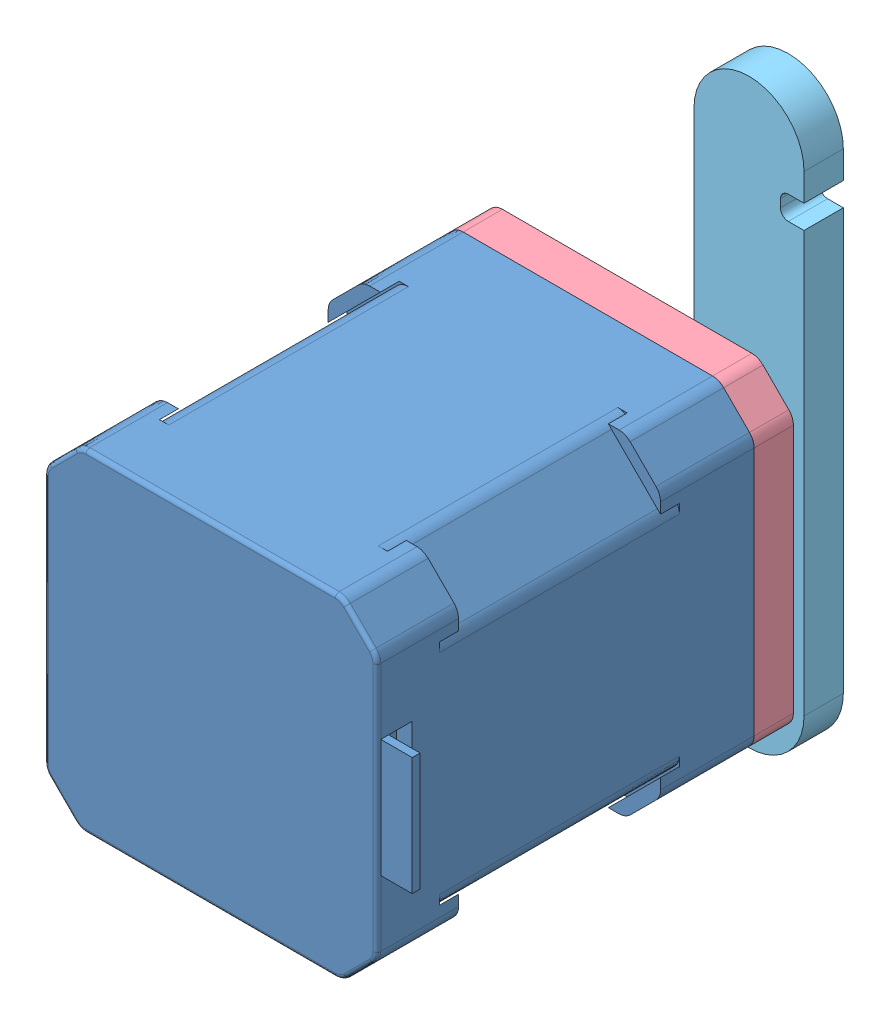
SolidWorks assembly Assem1, configuration Default. Lengths in mm.
Overall size (46.3 74 70).
5 component instances, 5 part files, 13 mates.
Components (placement in the parent):
- 400515-1: 400515 [Default] at origin size (46.3 42.3 70)
- 401369-1: 401369 [25] at (0 0 -12.2) size (14.14 14.12 22.3)
- Bearing 3ID 10OD 4W-1: Bearing 3ID 10OD 4W [Default] at (12.75 0 -12.2) size (11.5 11.5 4)
- Hook plate-1: Hook plate [Default] x (-1 0 0) z (0 0 -1) size (42.3 42.3 5)
- Arm-1: Arm [Default] at (0 0 -5) x (-1 0 0) z (0 0 -1) size (14 74 5)
Mates (geometry in assembly coordinates):
- Coincident1: coincident anti-aligned: plane of 400515-1 through (-7.6214 0 1) normal (0 0 -1); plane of 401369-1 through (0 0 1) normal (0 0 1)
- Concentric1: concentric aligned: cylinder of 400515-1 through (0 0 -22) axis (0 0 1) radius 2.5; cylinder of 401369-1 through (0 0 -21.3) axis (0 0 1) radius 6.35
- Coincident2: coincident aligned: plane of 401369-1 through (0 0 -12.2) normal (0 0 1); plane of Bearing 3ID 10OD 4W-1 through (12.75 0 -12.2) normal (0 0 1)
- Tangent1: tangent anti-aligned: cylinder of 401369-1 through (0 0 -21.3) axis (0 0 1) radius 7; cylinder of Bearing 3ID 10OD 4W-1 through (12.75 0 -10.2) axis (0 0 -1) radius 5.75
- InPlace1: in place: plane of 400515-1 through (-21.15 21.15 0) normal (0 0 -1); plane of Hook plate-1 through (0 0 0) normal (0 0 -1); moOrthogonalPlaneRef_w of 400515-1 through (-21.15 21.15 0) normal (0 0 -1); line of Hook plate-1 through (-55 0 0) axis (0 0 1); plane of 400515-1 through (-21.15 21.15 0) normal (0 0 -1); plane of Hook plate-1 through (0 0 0) normal (-1 0 0); plane of 400515-1 through (-21.15 21.15 0) normal (0 0 -1); unknown of Hook plate-1
- Coincident3: coincident aligned: plane of 400515-1; plane of Hook plate-1
- Coincident4: coincident aligned: moOrthogonalPlaneRef_w of 400515-1 through (0 0 0) normal (0 1 0); plane of Hook plate-1
- Coincident5: coincident anti-aligned: moOrthogonalPlaneRef_w of 400515-1 through (0 0 0) normal (1 0 0); plane of Hook plate-1 through (0 0 0) normal (-1 0 0)
- InPlace2: in place: plane of Hook plate-1 through (19.15 -15.8672 -5) normal (0 0 -1); plane of Arm-1 through (0 0 -5) normal (0 0 -1); plane of Hook plate-1 through (19.15 -15.8672 -5) normal (0 0 -1); unknown of Arm-1; plane of Hook plate-1 through (19.15 -15.8672 -5) normal (0 0 -1); plane of Arm-1 through (0 0 -5) normal (-1 0 0); plane of Hook plate-1 through (19.15 -15.8672 -5) normal (0 0 -1); unknown of Arm-1
- Coincident6: coincident aligned: plane of Hook plate-1; plane of Arm-1
- Coincident7: coincident aligned: moOrthogonalPlaneRef_w of Hook plate-1 through (0 0 -5) normal (0 1 0); plane of Arm-1
- Coincident8: coincident anti-aligned: moOrthogonalPlaneRef_w of Hook plate-1 through (0 0 -5) normal (1 0 0); plane of Arm-1 through (0 0 -5) normal (-1 0 0)
- Coincident11: coincident aligned: plane of 400515-1 through (0 0 0) normal (0 1 0); plane of Bearing 3ID 10OD 4W-1 through (12.75 0 -12.2) normal (0 1 0)
